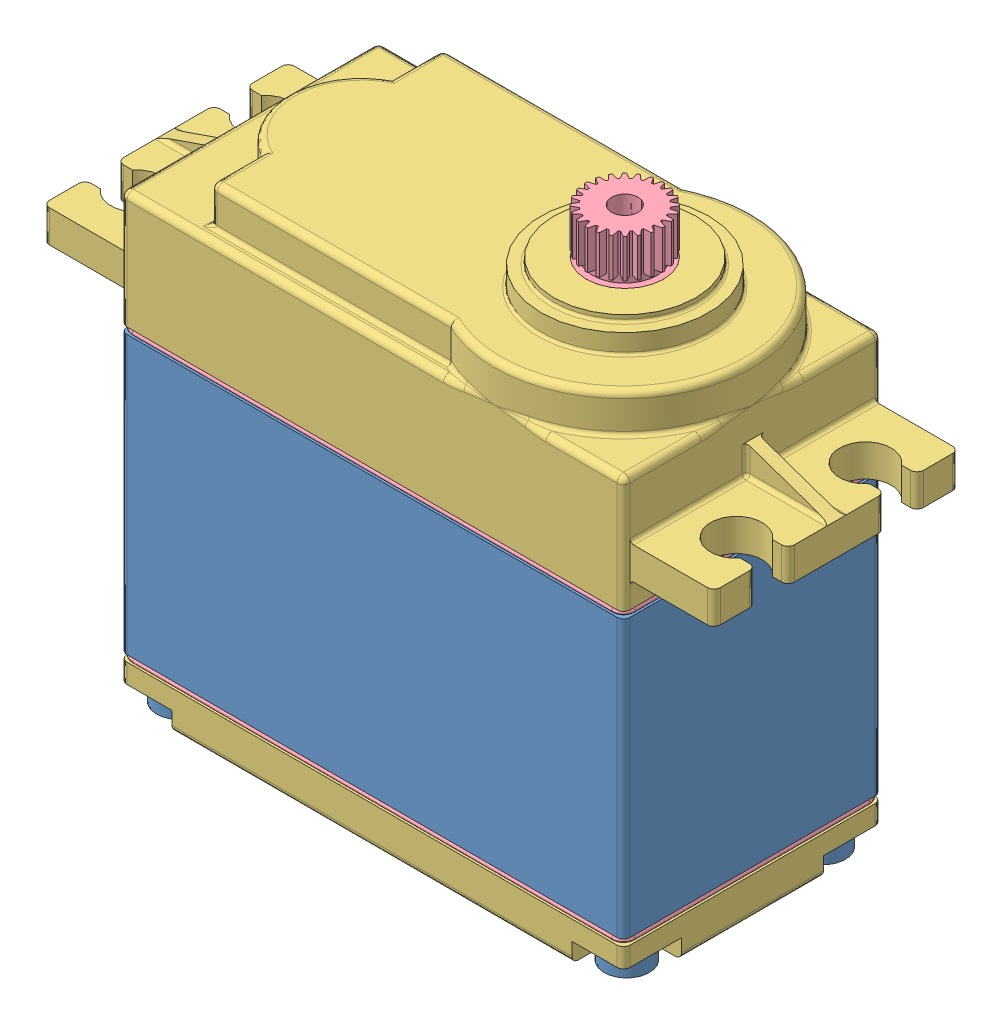
SolidWorks assembly РМ1, configuration Полный. Lengths in mm.
Overall size (52 43 23.81).
64 component instances, 28 part files, 82 mates.
Components (placement in the parent):
- Корпус-2: Корпус [По умолчанию] at origin
- Плата-1: Плата [По умолчанию] at (0 -10.5 0) x (-1 0 0) z (0 0 -1)
- Крышка-1: Крышка [По умолчанию] at (0 -13 0) x (-1 0 0) z (0 0 1)
- G1-1: G1 [Spur01] at (9.6 15.75 0) x (0.200367 0 0.979721) z (0 1 0)
- G2-1: G2 [Spur02] at (-1.2 16.75 0) x (-0.962765 0 -0.270339) z (0 1 0)
- G3-1: G3 [G3] at (-1.2 19.25 0) x (-0.270339 0 0.962765) z (0 1 0)
- G4-1: G4 [G4] at (-9.9 18.5 0) x (0.896706 0 0.442627) z (0 -1 0)
- G5-1: G5 [G6] at (-9.9 12.5 0) x (-0.896706 0 -0.442627) z (0 1 0)
- G6-1: G6 [G5] at (-1.2 12 0) x (0.073044 0 -0.997329) z (0 -1 0)
- G7-1: G7 [G7] at (-1.2 11.25 0) x (0.997329 0 0.073044) z (0 -1 0)
- G8-1: G8 [П8] at (-9.7 11.25 0) x (-0.199884 0 0.97982) z (0 -1 0)
- Пласт2-1: Пласт2 [По умолчанию] at (9.6 16.5 0) x (0.200367 0 0.979721) z (0.979721 0 -0.200367)
- Пласт1-1: Пласт1 [По умолчанию] at (9.6 14.5 0) x (-0.200367 0 -0.979721) z (0.979721 0 -0.200367)
- Ось-1: Ось [По умолчанию] at (-1.2 15.75 0) x (0.961755 0 0.273911) z (0.273911 0 -0.961755)
- Ось1-1: Ось1 [По умолчанию] at (-9.9 18.75 0) x (0.831133 0 0.556074) z (-0.556074 0 0.831133)
- Подшипник_1-1: Подшипник_1 [По умолчанию] at (9.6 13.5 0) size (14.01 2 14.01)
  - Вн_кольцо-1: Вн_кольцо [По умолчанию] at origin size (7 2 7)
  - Нар_кольцо-2: Нар_кольцо [По умолчанию] x (0.605705 0 -0.795689) z (0.795689 0 0.605705) size (10 2 10)
  - Шарик-1: Шарик [По умолчанию] at (-3.9953 0 0.1946) size (1.5 1.5 1.5)
  - Шарик-2: Шарик [По умолчанию] at (-3.3466 0 -2.1909) x (0.809017 0 0.587785) z (-0.587785 0 0.809017) size (1.5 1.5 1.5)
  - Шарик-3: Шарик [По умолчанию] at (-1.4197 0 -3.7396) x (0.309017 0 0.951057) z (-0.951057 0 0.309017) size (1.5 1.5 1.5)
  - Шарик-4: Шарик [По умолчанию] at (1.0495 0 -3.8599) x (-0.309017 0 0.951057) z (-0.951057 0 -0.309017) size (1.5 1.5 1.5)
  - Шарик-5: Шарик [По умолчанию] at (3.1179 0 -2.5058) x (-0.809017 0 0.587785) z (-0.587785 0 -0.809017) size (1.5 1.5 1.5)
  - Шарик-6: Шарик [По умолчанию] at (3.9953 0 -0.1946) x (-1 0 0) z (0 0 -1) size (1.5 1.5 1.5)
  - Шарик-7: Шарик [По умолчанию] at (3.3466 0 2.1909) x (-0.809017 0 -0.587785) z (0.587785 0 -0.809017) size (1.5 1.5 1.5)
  - Шарик-8: Шарик [По умолчанию] at (1.4197 0 3.7396) x (-0.309017 0 -0.951057) z (0.951057 0 -0.309017) size (1.5 1.5 1.5)
  - Шарик-9: Шарик [По умолчанию] at (-1.0495 0 3.8599) x (0.309017 0 -0.951057) z (0.951057 0 0.309017) size (1.5 1.5 1.5)
  - Шарик-10: Шарик [По умолчанию] at (-3.1179 0 2.5058) x (0.809017 0 -0.587785) z (0.587785 0 0.809017) size (1.5 1.5 1.5)
- Винт-1: Винт [По умолчанию] at (17.35 0.5 7.6) x (0.946284 0 0.323336) z (0.323336 0 -0.946284)
- Упл_кольцо-1: Упл_кольцо [По умолчанию] at (17.35 -13.5 7.6) x (0.852696 0 0.522408) z (-0.522408 0 0.852696)
- Винт-2: Винт [По умолчанию] at (17.35 0 -7.6) x (0.966388 0 0.257088) z (0.257088 0 -0.966388) (suppressed, hidden)
- Упл_кольцо-2: Упл_кольцо [По умолчанию] at (17.35 -14 -7.6) (suppressed, hidden)
- Винт-3: Винт [По умолчанию] at (-17.35 0 -7.6) x (-0.966388 0 0.257088) z (0.257088 0 0.966388) (suppressed, hidden)
- Упл_кольцо-3: Упл_кольцо [По умолчанию] at (-17.35 -14 -7.6) x (-1 0 0) z (0 0 -1) (suppressed, hidden)
- Упл_кольцо-4: Упл_кольцо [По умолчанию] at (-17.35 -14 7.6) x (-1 0 0) z (0 0 -1) (suppressed, hidden)
- Винт-4: Винт [По умолчанию] at (-17.35 0 7.6) x (-0.966388 0 -0.257088) z (-0.257088 0 0.966388) (suppressed, hidden)
- Основание-1: Основание [По умолчанию] at (0 15 0) x (-1 0 0) z (0 0 -1)
- Подшипник_1-2: Подшипник_1 [По умолчанию] at (9.6 22 0) size (14.01 2 14.01)
  - Вн_кольцо-1: Вн_кольцо [По умолчанию] at origin size (7 2 7)
  - Нар_кольцо-2: Нар_кольцо [По умолчанию] x (0.605705 0 -0.795689) z (0.795689 0 0.605705) size (10 2 10)
  - Шарик-1: Шарик [По умолчанию] at (-3.9953 0 0.1946) size (1.5 1.5 1.5)
  - Шарик-2: Шарик [По умолчанию] at (-3.3466 0 -2.1909) x (0.809017 0 0.587785) z (-0.587785 0 0.809017) size (1.5 1.5 1.5)
  - Шарик-3: Шарик [По умолчанию] at (-1.4197 0 -3.7396) x (0.309017 0 0.951057) z (-0.951057 0 0.309017) size (1.5 1.5 1.5)
  - Шарик-4: Шарик [По умолчанию] at (1.0495 0 -3.8599) x (-0.309017 0 0.951057) z (-0.951057 0 -0.309017) size (1.5 1.5 1.5)
  - Шарик-5: Шарик [По умолчанию] at (3.1179 0 -2.5058) x (-0.809017 0 0.587785) z (-0.587785 0 -0.809017) size (1.5 1.5 1.5)
  - Шарик-6: Шарик [По умолчанию] at (3.9953 0 -0.1946) x (-1 0 0) z (0 0 -1) size (1.5 1.5 1.5)
  - Шарик-7: Шарик [По умолчанию] at (3.3466 0 2.1909) x (-0.809017 0 -0.587785) z (0.587785 0 -0.809017) size (1.5 1.5 1.5)
  - Шарик-8: Шарик [По умолчанию] at (1.4197 0 3.7396) x (-0.309017 0 -0.951057) z (0.951057 0 -0.309017) size (1.5 1.5 1.5)
  - Шарик-9: Шарик [По умолчанию] at (-1.0495 0 3.8599) x (0.309017 0 -0.951057) z (0.951057 0 0.309017) size (1.5 1.5 1.5)
  - Шарик-10: Шарик [По умолчанию] at (-3.1179 0 2.5058) x (0.809017 0 -0.587785) z (0.587785 0 0.809017) size (1.5 1.5 1.5)
- Прокл-1: Прокл [По умолчанию] at (0 -11.75 0) x (1 0 0) z (0 0 1)
- Прокл-2: Прокл [По умолчанию] at (0 10.25 0)
- Винт-8: Винт [По умолчанию] at (17.35 0.5 -7.6) x (0.946284 0 0.323336) z (0.323336 0 -0.946284)
- Упл_кольцо-5: Упл_кольцо [По умолчанию] at (17.35 -13.5 -7.6) x (0.852696 0 0.522408) z (-0.522408 0 0.852696)
- Винт-9: Винт [По умолчанию] at (-17.35 0.5 7.6) x (0.946284 0 0.323336) z (0.323336 0 -0.946284)
- Упл_кольцо-6: Упл_кольцо [По умолчанию] at (-17.35 -13.5 7.6) x (0.852696 0 0.522408) z (-0.522408 0 0.852696)
- Винт-10: Винт [По умолчанию] at (-17.35 0.5 -7.6) x (0.946284 0 0.323336) z (0.323336 0 -0.946284)
- Упл_кольцо-7: Упл_кольцо [По умолчанию] at (-17.35 -13.5 -7.6) x (0.852696 0 0.522408) z (-0.522408 0 0.852696)
- Штырь-1: Штырь [По умолчанию] at (15.9682 17 -1.3024) x (-0.26515 0 -0.964207) z (0.964207 0 -0.26515)
- Дв_корп-1: Дв_корп [По умолчанию] at (-9.7 0 0)
- Дв_вал-1: Дв_вал [По умолчанию] at (-9.7 7 0)
- Дв_крышка-1: Дв_крышка [По умолчанию] at (-9.7 -9.5 0) x (-0.837169 0 -0.546944) z (-0.546944 0 0.837169)
- Птнц_корп-1: Птнц_корп [По умолчанию] at (9.6 5 0)
- Птнц_вал-1: Птнц_вал [По умолчанию] at (9.6 12.5 0) x (-0.200367 0 -0.979721) z (0.979721 0 -0.200367)
Mates (geometry in assembly coordinates):
- Совпадение7: coincident anti-aligned: plane of Корпус-2 through (0 -10 -32.5618) normal (0 -1 0); plane of Плата-1 through (32.5618 -10 0) normal (0 1 0)
- Совпадение8: coincident anti-aligned: plane of Корпус-2 through (19.5 -11 -9.2) normal (0 0 1); plane of Плата-1 through (32.5618 -10 -9.2) normal (0 0 -1)
- Совпадение9: coincident anti-aligned: plane of Корпус-2 through (18.7 -11 -10) normal (-1 0 0); plane of Плата-1 through (18.7 -10 0) normal (1 0 0)
- Совпадение10: coincident anti-aligned: plane of Корпус-2 through (18.7 -11 -9.2) normal (0 -1 0); plane of Крышка-1 through (19.5 -11 -10) normal (0 1 0)
- Совпадение12: coincident anti-aligned: plane of Корпус-2 through (19.5 -11 -9.2) normal (0 0 1); plane of Крышка-1 through (-18.7 -12 -9.2) normal (0 0 -1)
- Совпадение13: coincident anti-aligned: plane of Корпус-2 through (-18.7 -11 -10) normal (1 0 0); plane of Крышка-1 through (-18.7 -12 9.2) normal (-1 0 0)
- Концентричный1: concentric aligned: cylinder of G2-1 through (-1.2 18.25 0) axis (0 1 0) radius 2.5; cylinder of G3-1 through (-1.2 11.1789 0) axis (0 1 0) radius 2.5
- Совпадение14: coincident anti-aligned: plane of G2-1 through (-1.2 18.25 0) normal (0 1 0); plane of G3-1 through (5.1542 18.25 1.7842) normal (0 -1 0)
- Концентричный2: concentric anti-aligned: cylinder of G4-1 through (-9.9 17.5 0) axis (0 -1 0) radius 2.4; cylinder of G5-1 through (-9.9 9.7118 0) axis (0 1 0) radius 2.4
- Совпадение15: coincident anti-aligned: plane of G4-1 through (-9.9 17.5 0) normal (0 -1 0); plane of G5-1 through (-9.9 17.5 0) normal (0 1 0)
- Концентричный3: concentric aligned: cylinder of G6-1 through (-1.2 11.75 0) axis (0 -1 0) radius 1.75; cylinder of G7-1 through (-1.2 16.6997 0) axis (0 -1 0) radius 1.75
- Совпадение16: coincident anti-aligned: plane of G6-1 through (-7.9234 11.75 -0.4924) normal (0 -1 0); plane of G7-1 through (-1.7478 11.75 7.48) normal (0 1 0)
- Концентричный4: concentric anti-aligned: cylinder of Пласт2-1 through (9.6 8.4289 0) axis (0 1 0) radius 2.5; cylinder of Пласт1-1 through (9.6 16 0) axis (0 -1 0) radius 2.5
- Концентричный5: concentric anti-aligned: cylinder of Пласт2-1 through (4.7014 14.5 1.0018) axis (0 1 0) radius 1.5; cylinder of Пласт1-1 through (4.7014 15.5 1.0018) axis (0 -1 0) radius 1.5
- Совпадение17: coincident anti-aligned: plane of Пласт2-1 through (7.5025 15.5 -10.8175) normal (0 -1 0); plane of Пласт1-1 through (11.8156 15.5 10.9588) normal (0 1 0)
- Концентричный6: concentric aligned: cylinder of G1-1 through (9.6 19 0) axis (0 -1 0) radius 3; cylinder of Пласт2-1 through (9.6 17.5 0) axis (0 -1 0) radius 3
- Совпадение18: coincident aligned: plane of G1-1; plane of Пласт2-1
- Совпадение19: coincident anti-aligned: plane of G1-1 through (9.6 16.5 0) normal (0 -1 0); plane of Пласт2-1 through (7.3352 16.5 -10.9487) normal (0 1 0)
- Концентричный7: concentric anti-aligned: cylinder of G6-1 through (-1.2 15.3713 0) axis (0 -1 0) radius 0.75; cylinder of Ось-1 through (-1.2 9.5 0) axis (0 1 0) radius 0.75
- Совпадение21: coincident aligned: plane of G7-1 through (-1.2 11.25 0) normal (0 -1 0); plane of G8-1 through (-9.7 11.25 0) normal (0 -1 0)
- Совпадение23: coincident: line of G7-1 through (-1.2 -43.75 0) axis (0 1 0); plane of assembly
- Совпадение25: coincident anti-aligned: plane of Корпус-2 through (-1.2 9.5 0) normal (0 1 0); plane of Ось-1 through (-1.2 9.5 0) normal (0 -1 0)
- Совпадение26: coincident anti-aligned: plane of Корпус-2 through (-30.4875 10.75 0) normal (0 1 0); plane of G6-1 through (-1.2 10.75 0) normal (0 -1 0)
- Концентричный8: concentric aligned: cylinder of Корпус-2 through (-1.2 9.5 0) axis (0 1 0) radius 0.75; cylinder of Ось-1 through (-1.2 9.5 0) axis (0 1 0) radius 0.75
- Концентричный9: concentric aligned: cylinder of G4-1 through (-9.9 18.5 0) axis (0 -1 0) radius 0.75; cylinder of Ось1-1 through (-9.9 22 0) axis (0 -1 0) radius 0.75
- Совпадение32: coincident aligned: plane of G6-1; plane of G7-1
- Совпадение33: coincident anti-aligned: plane of G4-1; plane of G5-1
- Концентричный10: concentric aligned: cylinder of G2-1 through (-1.2 11.1287 0) axis (0 1 0) radius 0.75; cylinder of Ось-1 through (-1.2 9.5 0) axis (0 1 0) radius 0.75
- Совпадение34: coincident anti-aligned: plane of G2-1 through (-2.011 13.25 2.8883) normal (0 -1 0); plane of G6-1 through (0.8944 13.25 0.1534) normal (0 1 0)
- Совпадение35: coincident anti-aligned: plane of G2-1; plane of G3-1
- Концентричный11: concentric aligned: cylinder of Корпус-2 through (9.6 14.5 0) axis (0 -1 0) radius 3; cylinder of Подшипник_1-1/Вн_кольцо-1 through (9.6 14.5 0) axis (0 -1 0) radius 3
- Совпадение36: coincident anti-aligned: plane of Корпус-2 through (9.6 12.5 0) normal (0 1 0); plane of Подшипник_1-1/Вн_кольцо-1 through (9.6 12.5 0) normal (0 -1 0)
- Концентричный13: concentric aligned: cylinder of G1-1 through (9.6 16.5 0) axis (0 -1 0) radius 5; cylinder of Подшипник_1-1/Нар_кольцо-2 through (9.6 14.5 0) axis (0 -1 0) radius 5
- Совпадение39: coincident anti-aligned: plane of Пласт1-1 through (11.8156 14.5 10.9588) normal (0 -1 0); plane of Подшипник_1-1/Нар_кольцо-2 through (9.6 14.5 0) normal (0 1 0)
- Сопряжения редуктора5: gear = 5.2 : 16.4 mm: circle of G1-1; circle of G2-1
- Совпадение40: coincident anti-aligned: plane of Корпус-2 through (-14.4414 15.5 0) normal (0 1 0); plane of Ось1-1 through (-9.9 15.5 0) normal (0 -1 0)
- Концентричный16: concentric anti-aligned: cylinder of Корпус-2 through (-9.9 15.5 0) axis (0 1 0) radius 0.75; cylinder of Ось1-1 through (-9.9 22 0) axis (0 -1 0) radius 0.75
- Совпадение41: coincident anti-aligned: plane of Корпус-2 through (-17.7642 16.5 0) normal (0 1 0); plane of G4-1 through (-9.9 16.5 0) normal (0 -1 0)
- Концентричный19: concentric aligned: cylinder of Корпус-2 through (-9.7 11.9142 0) axis (0 -1 0) radius 0.5; circle of G8-1
- Сопряжения редуктора6: gear = 2.5 : 14.5 mm: circle of G7-1; circle of G8-1
- Сопряжения редуктора7: gear = 3.6 : 13.8 mm: circle of G5-1; circle of G6-1
- Сопряжения редуктора8: gear = 4.8 : 12.6 mm: circle of G3-1; circle of G4-1
- Концентричный20: concentric aligned: cylinder of Крышка-1 through (17.35 -13 7.6) axis (0 -1 0) radius 1.6; cylinder of Упл_кольцо-1 through (17.35 -13 7.6) axis (0 -1 0) radius 1.6
- Совпадение43: coincident anti-aligned: plane of Винт-1 through (17.35 -13.5 7.6) normal (0 1 0); plane of Упл_кольцо-1 through (17.35 -13.5 7.6) normal (0 -1 0)
- Концентричный24: concentric aligned: cylinder of Крышка-1 through (17.35 -8.1716 7.6) axis (0 -1 0) radius 1; cylinder of Винт-1 through (17.35 -15 7.6) axis (0 -1 0) radius 0.8
- Совпадение48: coincident anti-aligned: plane of Основание-1 through (0 15 0) normal (0 0 -1); plane of assembly through (0 0 0) normal (0 0 1)
- Концентричный25: concentric aligned: cylinder of Основание-1 through (9.6 23 0) axis (0 -1 0) radius 5; cylinder of Подшипник_1-2/Нар_кольцо-2 through (9.6 23 0) axis (0 -1 0) radius 5
- Совпадение49: coincident anti-aligned: plane of Основание-1 through (9.6 23 0) normal (0 -1 0); plane of Подшипник_1-2/Нар_кольцо-2 through (9.6 23 0) normal (0 1 0)
- Совпадение50: coincident anti-aligned: plane of Основание-1 through (0 15 0) normal (-1 0 0); plane of assembly through (0 0 0) normal (1 0 0)
- Касательность1: tangent: plane of Корпус-2 through (19.5 -11.5 -10) normal (0 -1 0); face of Прокл-1
- Касательность2: tangent: plane of Крышка-1 through (18.7 -12 -9.2) normal (1 0 0); face of Прокл-1
- Касательность3: tangent: plane of Крышка-1 through (-18.7 -12 -9.2) normal (0 0 -1); face of Прокл-1
- Совпадение51: coincident anti-aligned: plane of Корпус-2 through (19.5 11.5 -10) normal (0 1 0); plane of Основание-1 through (-18.7 11.5 9.2) normal (0 -1 0)
- Совпадение52: coincident aligned: plane of Корпус-2 through (0 0 0) normal (0 0 1); plane of Прокл-2 through (0 10.25 0) normal (0 0 1)
- Совпадение53: coincident aligned: plane of Корпус-2 through (0 0 0) normal (1 0 0); plane of Прокл-2 through (0 10.25 0) normal (1 0 0)
- Расстояние1: distance = 0.25 mm aligned: plane of Корпус-2 through (-34.2325 10 0) normal (0 1 0); plane of Прокл-2 through (0 10.25 0) normal (0 1 0)
- Совпадение58: coincident anti-aligned: plane of Крышка-1 through (17.35 -13 7.6) normal (0 -1 0); plane of Упл_кольцо-1 through (17.35 -13 7.6) normal (0 1 0)
- Совпадение59: coincident anti-aligned: plane of Винт-8 through (17.35 -13.5 -7.6) normal (0 1 0); plane of Упл_кольцо-5 through (17.35 -13.5 -7.6) normal (0 -1 0)
- Концентричный29: concentric aligned: cylinder of Крышка-1 through (17.35 -13 -7.6) axis (0 -1 0) radius 1.6; cylinder of Упл_кольцо-5 through (17.35 -13 -7.6) axis (0 -1 0) radius 1.6
- Концентричный30: concentric aligned: cylinder of Крышка-1 through (17.35 -8.1716 -7.6) axis (0 -1 0) radius 1; cylinder of Винт-8 through (17.35 -15 -7.6) axis (0 -1 0) radius 0.8
- Совпадение60: coincident anti-aligned: plane of Крышка-1 through (17.35 -13 -7.6) normal (0 -1 0); plane of Упл_кольцо-5 through (17.35 -13 -7.6) normal (0 1 0)
- Совпадение61: coincident anti-aligned: plane of Винт-9 through (-17.35 -13.5 7.6) normal (0 1 0); plane of Упл_кольцо-6 through (-17.35 -13.5 7.6) normal (0 -1 0)
- Концентричный31: concentric aligned: cylinder of Крышка-1 through (-17.35 -13 7.6) axis (0 -1 0) radius 1.6; cylinder of Упл_кольцо-6 through (-17.35 -13 7.6) axis (0 -1 0) radius 1.6
- Концентричный32: concentric aligned: cylinder of Крышка-1 through (-17.35 -8.1716 7.6) axis (0 -1 0) radius 1; cylinder of Винт-9 through (-17.35 -15 7.6) axis (0 -1 0) radius 0.8
- Совпадение62: coincident anti-aligned: plane of Крышка-1 through (-17.35 -13 7.6) normal (0 -1 0); plane of Упл_кольцо-6 through (-17.35 -13 7.6) normal (0 1 0)
- Совпадение63: coincident anti-aligned: plane of Винт-10 through (-17.35 -13.5 -7.6) normal (0 1 0); plane of Упл_кольцо-7 through (-17.35 -13.5 -7.6) normal (0 -1 0)
- Концентричный33: concentric aligned: cylinder of Крышка-1 through (-17.35 -13 -7.6) axis (0 -1 0) radius 1.6; cylinder of Упл_кольцо-7 through (-17.35 -13 -7.6) axis (0 -1 0) radius 1.6
- Концентричный34: concentric aligned: cylinder of Крышка-1 through (-17.35 -8.1716 -7.6) axis (0 -1 0) radius 1; cylinder of Винт-10 through (-17.35 -15 -7.6) axis (0 -1 0) radius 0.8
- Совпадение64: coincident anti-aligned: plane of Крышка-1 through (-17.35 -13 -7.6) normal (0 -1 0); plane of Упл_кольцо-7 through (-17.35 -13 -7.6) normal (0 1 0)
- Концентричный35: concentric anti-aligned: cylinder of G1-1 through (15.9682 9.6716 -1.3024) axis (0 1 0) radius 1; cylinder of Штырь-1 through (15.9682 20.5 -1.3024) axis (0 -1 0) radius 1
- Совпадение65: coincident aligned: plane of G1-1 through (18.0256 13.5 -1.7232) normal (0 -1 0); plane of Штырь-1 through (15.9682 13.5 -1.3024) normal (0 -1 0)
- Совпадение66: coincident anti-aligned: plane of Корпус-2 through (0 9 -33.3273) normal (0 -1 0); plane of Дв_корп-1 through (-10.2 9 0) normal (0 1 0)
- Концентричный36: concentric aligned: cylinder of Дв_корп-1 through (-9.7 -16.8719 0) axis (0 -1 0) radius 0.5; cylinder of Дв_вал-1 through (-9.7 12 0) axis (0 -1 0) radius 0.5
- Расстояние2: distance = 3 mm aligned: plane of Дв_вал-1 through (-9.7 12 0) normal (0 1 0); plane of Дв_корп-1 through (-10.2 9 0) normal (0 1 0)
- Концентричный37: concentric aligned: cylinder of G8-1 through (-9.7 13.1642 0) axis (0 -1 0) radius 0.5; cylinder of Дв_вал-1 through (-9.7 12 0) axis (0 -1 0) radius 0.5
- Концентричный38: concentric anti-aligned: cylinder of Дв_корп-1 through (-9.7 -16.8719 0) axis (0 -1 0) radius 7.6; cylinder of Дв_крышка-1 through (-9.7 -9 0) axis (0 1 0) radius 7.6
- Совпадение67: coincident anti-aligned: plane of Плата-1 through (32.5618 -10 0) normal (0 1 0); plane of Дв_крышка-1 through (-9.7 -10 0) normal (0 -1 0)
- Концентричный41: concentric anti-aligned: cylinder of Птнц_корп-1 through (9.6 7 0) axis (0 1 0) radius 2; cylinder of Птнц_вал-1 through (9.6 18 0) axis (0 -1 0) radius 2
- Концентричный42: concentric anti-aligned: cylinder of Корпус-2 through (9.6 3.3431 0) axis (0 1 0) radius 2; cylinder of Птнц_вал-1 through (9.6 18 0) axis (0 -1 0) radius 2
- Совпадение71: coincident anti-aligned: plane of Корпус-2 through (0 9 -33.3273) normal (0 -1 0); plane of Птнц_корп-1 through (4.6 9 0) normal (0 1 0)
- Совпадение72: coincident anti-aligned: plane of Пласт1-1 through (9.7506 10.0279 5.7274) normal (0.979721 0 -0.200367); plane of Птнц_вал-1 through (9.0212 16 2.1608) normal (-0.979721 0 0.200367)
- Совпадение73: coincident anti-aligned: plane of Птнц_корп-1 through (7.6 7 0) normal (0 1 0); plane of Птнц_вал-1 through (9.6 7 0) normal (0 -1 0)
